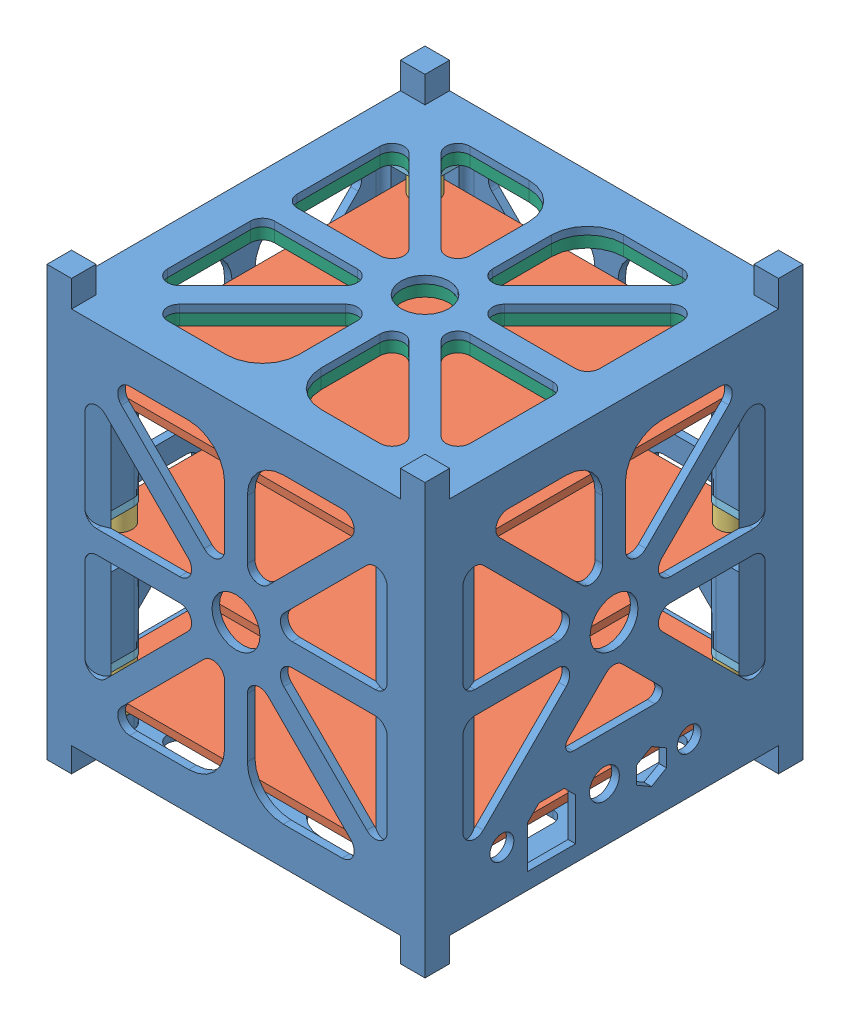
SolidWorks assembly Assem2, configuration Default. Lengths in mm.
Overall size (100 113.5 100).
53 component instances, 6 part files, 15 mates.
Components (placement in the parent):
- Part1-1: Part1 [Default] at (32.5928 65.2098 88.2162) size (100 113.5 100)
- board-1: board [Default] at (32.5055 26.2098 88.4112) size (92 2 92)
- spacer-1: spacer [Default] at (-7.9072 21.2098 47.7162) size (7.07 5 7.07)
- spacer-2: spacer [Default] at (73.0928 21.2098 47.7162) x (-1 0 0) z (0 0 -1) size (7.07 5 7.07) (hidden)
- rod-1: rod [Default] at (-7.9072 19.2098 47.7162) size (3 16 3)
- spacer-3: spacer [Default] at (-7.9072 28.2098 47.7162) size (7.07 5 7.07)
- board over hang clips-1: board over hang clips [Default] at (-9.4684 33.2098 46.5939) x (0 0 -1) z (1 0 0) size (11 2 11)
- spacer-4: spacer [Default] at (73.0928 28.2098 47.7162) x (-1 0 0) z (0 0 -1) size (7.07 5 7.07)
- rod-2: rod [Default] at (73.0928 19.2098 47.7162) x (-1 0 0) z (0 0 -1) size (3 16 3)
- board over hang clips-2: board over hang clips [Default] at (74.6539 35.2098 46.5939) x (0 0 -1) z (-1 0 0) size (11 2 11)
- spacer-5: spacer [Default] at (73.0928 28.2098 128.7162) x (-1 0 0) z (0 0 -1) size (7.07 5 7.07)
- rod-3: rod [Default] at (73.0928 19.2098 128.7162) x (-1 0 0) z (0 0 -1) size (3 16 3)
- board over hang clips-3: board over hang clips [Default] at (74.6539 33.2098 129.8385) x (0 0 1) z (-1 0 0) size (11 2 11)
- spacer-6: spacer [Default] at (-7.9072 21.2098 128.7162) size (7.07 5 7.07)
- rod-4: rod [Default] at (-7.9072 19.2098 128.7162) size (3 16 3)
- spacer-7: spacer [Default] at (-7.9072 28.2098 128.7162) size (7.07 5 7.07)
- board over hang clips-4: board over hang clips [Default] at (-9.4684 35.2098 129.8385) x (0 0 1) z (1 0 0) size (11 2 11)
- spacer-8: spacer [Default] at (73.0928 21.2098 128.7162) x (-1 0 0) z (0 0 -1) size (7.07 5 7.07)
- spacer-9: spacer [Default] at (73.0928 56.2098 128.7162) x (-1 0 0) z (0 0 -1) size (7.07 5 7.07)
- spacer-10: spacer [Default] at (73.0928 91.2098 128.7162) x (-1 0 0) z (0 0 -1) size (7.07 5 7.07)
- rod-5: rod [Default] at (73.0928 54.2098 128.7162) x (-1 0 0) z (0 0 -1) size (3 16 3)
- rod-6: rod [Default] at (73.0928 89.2098 128.7162) x (-1 0 0) z (0 0 -1) size (3 16 3)
- spacer-11: spacer [Default] at (73.0928 63.2098 128.7162) x (-1 0 0) z (0 0 -1) size (7.07 5 7.07)
- spacer-12: spacer [Default] at (73.0928 98.2098 128.7162) x (-1 0 0) z (0 0 -1) size (7.07 5 7.07)
- board over hang clips-5: board over hang clips [Default] at (74.6539 68.2098 129.8385) x (0 0 1) z (-1 0 0) size (11 2 11)
- board over hang clips-6: board over hang clips [Default] at (74.6539 103.2098 129.8385) x (0 0 1) z (-1 0 0) size (11 2 11)
- board over hang clips-7: board over hang clips [Default] at (-9.4684 70.2098 129.8385) x (0 0 1) z (1 0 0) size (11 2 11)
- board over hang clips-8: board over hang clips [Default] at (-9.4684 105.2098 129.8385) x (0 0 1) z (1 0 0) size (11 2 11)
- spacer-13: spacer [Default] at (-7.9072 56.2098 128.7162) size (7.07 5 7.07)
- spacer-14: spacer [Default] at (-7.9072 91.2098 128.7162) size (7.07 5 7.07)
- rod-7: rod [Default] at (-7.9072 54.2098 128.7162) size (3 16 3)
- rod-8: rod [Default] at (-7.9072 89.2098 128.7162) size (3 16 3)
- spacer-15: spacer [Default] at (-7.9072 63.2098 128.7162) size (7.07 5 7.07)
- spacer-16: spacer [Default] at (-7.9072 98.2098 128.7162) size (7.07 5 7.07)
- board over hang clips-9: board over hang clips [Default] at (-9.4684 68.2098 46.5939) x (0 0 -1) z (1 0 0) size (11 2 11)
- board over hang clips-10: board over hang clips [Default] at (-9.4684 103.2098 46.5939) x (0 0 -1) z (1 0 0) size (11 2 11)
- rod-9: rod [Default] at (-7.9072 54.2098 47.7162) size (3 16 3)
- rod-10: rod [Default] at (-7.9072 89.2098 47.7162) size (3 16 3)
- spacer-17: spacer [Default] at (-7.9072 56.2098 47.7162) size (7.07 5 7.07)
- spacer-18: spacer [Default] at (-7.9072 91.2098 47.7162) size (7.07 5 7.07)
- spacer-19: spacer [Default] at (-7.9072 63.2098 47.7162) size (7.07 5 7.07)
- spacer-20: spacer [Default] at (-7.9072 98.2098 47.7162) size (7.07 5 7.07)
- rod-11: rod [Default] at (73.0928 54.2098 47.7162) x (-1 0 0) z (0 0 -1) size (3 16 3)
- rod-12: rod [Default] at (73.0928 89.2098 47.7162) x (-1 0 0) z (0 0 -1) size (3 16 3)
- board over hang clips-11: board over hang clips [Default] at (74.6539 70.2098 46.5939) x (0 0 -1) z (-1 0 0) size (11 2 11)
- board over hang clips-12: board over hang clips [Default] at (74.6539 105.2098 46.5939) x (0 0 -1) z (-1 0 0) size (11 2 11)
- spacer-21: spacer [Default] at (73.0928 63.2098 47.7162) x (-1 0 0) z (0 0 -1) size (7.07 5 7.07)
- spacer-22: spacer [Default] at (73.0928 98.2098 47.7162) x (-1 0 0) z (0 0 -1) size (7.07 5 7.07)
- spacer-23: spacer [Default] at (73.0928 56.2098 47.7162) x (-1 0 0) z (0 0 -1) size (7.07 5 7.07)
- spacer-24: spacer [Default] at (73.0928 91.2098 47.7162) x (-1 0 0) z (0 0 -1) size (7.07 5 7.07)
- Part3-1: Part3 [Default] at (32.5928 110.2098 88.2162) size (96 3 96)
- board-2: board [Default] at (32.5055 61.2098 88.4112) size (92 2 92)
- board-3: board [Default] at (32.5055 96.2098 88.4112) size (92 2 92)
Mates (geometry in assembly coordinates):
- Coincident1: coincident anti-aligned: plane of Part1-1 through (32.5928 21.2098 88.2162) normal (0 1 0); plane of spacer-1 through (-7.9072 21.2098 47.7162) normal (0 -1 0)
- Coincident2: coincident aligned: circle of Part1-1; circle of spacer-1
- Coincident3: coincident anti-aligned: plane of Part1-1 through (32.5928 35.2098 88.2162) normal (0 -1 0); circle of rod-1
- Concentric1: concentric aligned: cylinder of spacer-1 through (-7.9072 26.2098 47.7162) axis (0 -1 0) radius 3.5355; cylinder of rod-1 through (-7.9072 35.2098 47.7162) axis (0 -1 0) radius 1.5
- Concentric3: concentric aligned: cylinder of rod-1 through (-7.9072 35.2098 47.7162) axis (0 -1 0) radius 1.5; cylinder of spacer-3 through (-7.9072 33.2098 47.7162) axis (0 -1 0) radius 3.5355
- Coincident5: coincident aligned: plane of Part1-1 through (32.5928 33.2098 88.2162) normal (0 1 0); circle of spacer-3
- Coincident6: coincident aligned: plane of Part1-1 through (32.5928 33.2098 88.2162) normal (0 1 0); plane of spacer-3 through (-7.9072 33.2098 47.7162) normal (0 1 0)
- Coincident7: coincident anti-aligned: plane of Part1-1 through (32.5928 35.2098 88.2162) normal (0 -1 0); plane of board over hang clips-1 through (-7.4072 35.2098 48.2162) normal (0 1 0)
- Concentric5: concentric aligned: circle of spacer-3; circle of board over hang clips-1
- Coincident8: coincident aligned: plane of Part1-1 through (-4.4072 -499934.7902 42.2162) normal (1 0 0); plane of board over hang clips-1 through (-4.4072 35.2098 48.2162) normal (1 0 0)
- Coincident9: coincident anti-aligned: plane of Part1-1 through (-15.4072 113.2098 136.2162) normal (0 -1 0); plane of Part3-1 through (32.5928 113.2098 88.2162) normal (0 1 0)
- Coincident10: coincident anti-aligned: plane of Part1-1 through (-15.4072 110.2098 53.2162) normal (1 0 0); plane of Part3-1 through (-15.4072 113.2098 92.2162) normal (-1 0 0)
- Coincident11: coincident anti-aligned: plane of Part1-1 through (-2.4072 110.2098 40.2162) normal (0 0 1); plane of Part3-1 through (28.5928 113.2098 40.2162) normal (0 0 -1)
- Coincident12: coincident anti-aligned: plane of board-1 through (32.5055 26.2098 88.4112) normal (0 -1 0); plane of spacer-1 through (-7.9072 26.2098 47.7162) normal (0 1 0)
- Concentric6: concentric aligned: circle of board-1; circle of spacer-1
